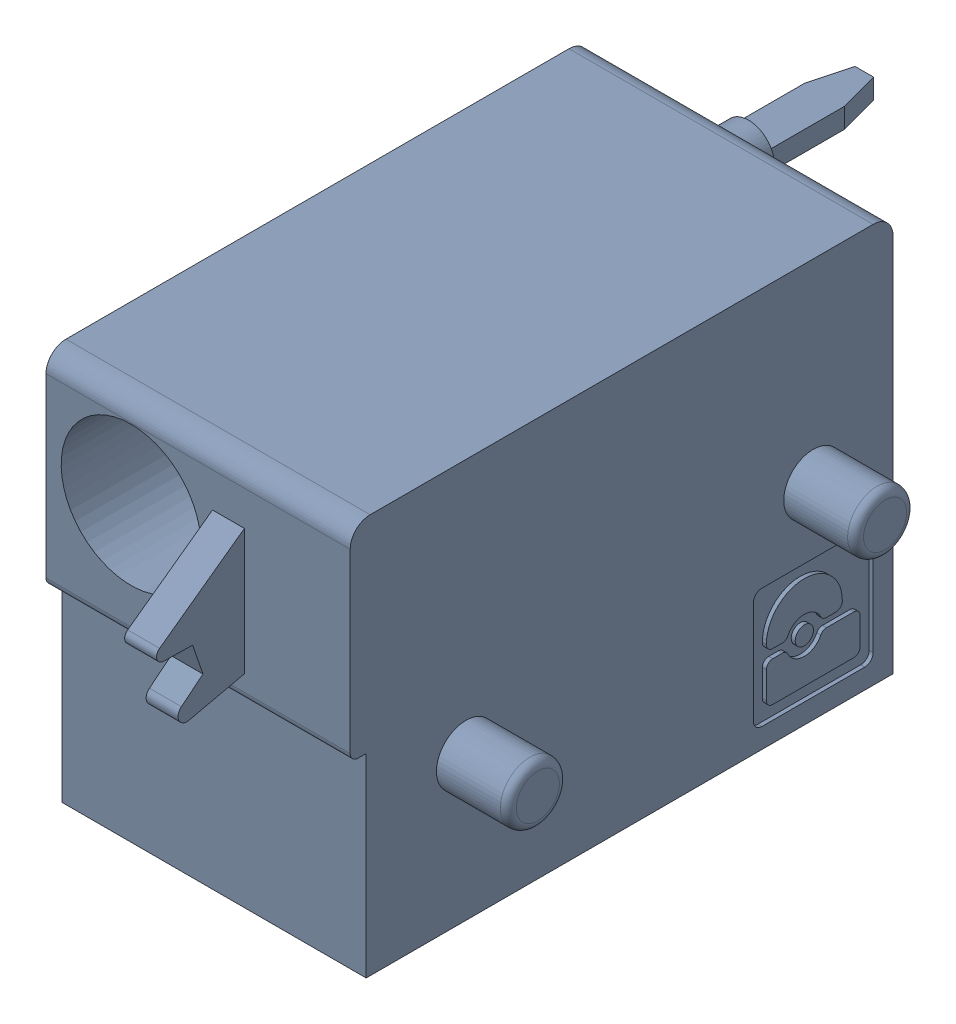
SolidWorks assembly J34, configuration Default. Lengths in mm.
Overall size (9.42 10 19.2).
2 component instances, 1 part files, 0 mates.
Components (placement in the parent):
- 1790377-1: 1790377 [Default] at (106.0451 -7.6199 0) x (0 1 0) z (1 0 0) size (10 19.2 9.42)
  - ffkdsa-v2-7.62-1: ffkdsa-v2-7.62 [Default] at (-23.7414 -38.158 -5.08) x (0 -1 0) z (0 0 1) size (19.2 10 9.42)
